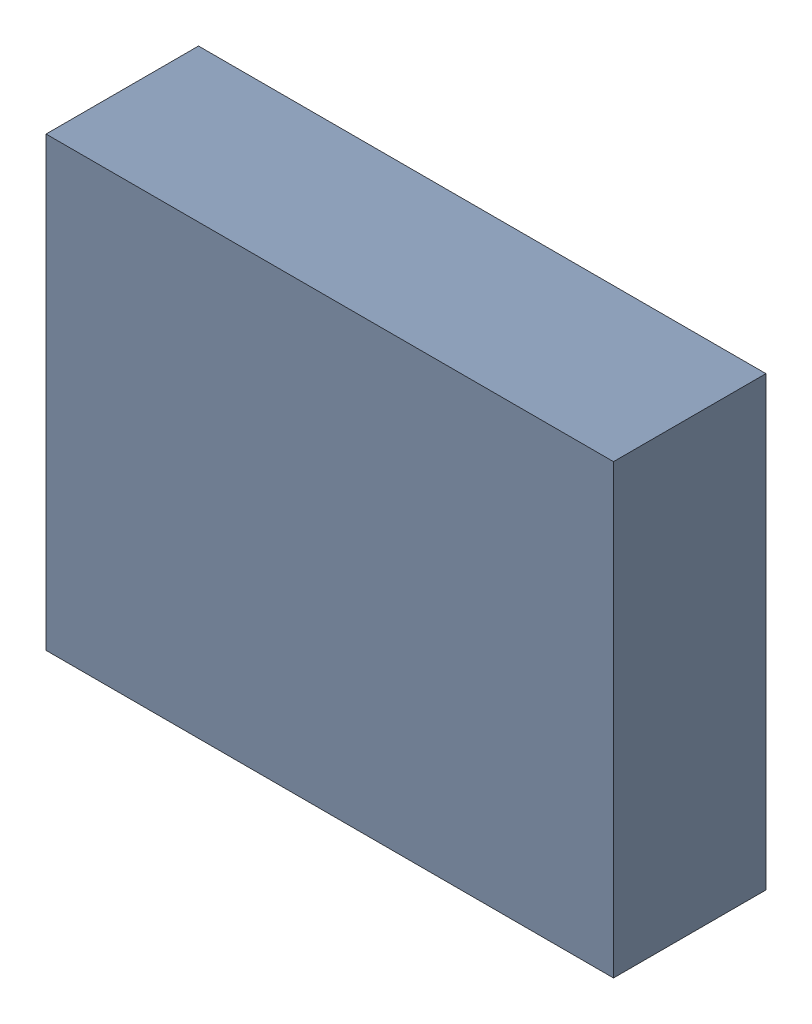
SolidWorks assembly PULL_B, configuration Default. Lengths in mm.
Overall size (3.35 2.64 0.9).
2 component instances, 1 part files, 0 mates.
Components (placement in the parent):
- 5920132160-1: 5920132160 [Default] at (46.25 38.75 0) size (3.35 2.64 0.9)
  - Extruded-1: Extruded [Default] at origin size (3.35 2.64 0.9)
